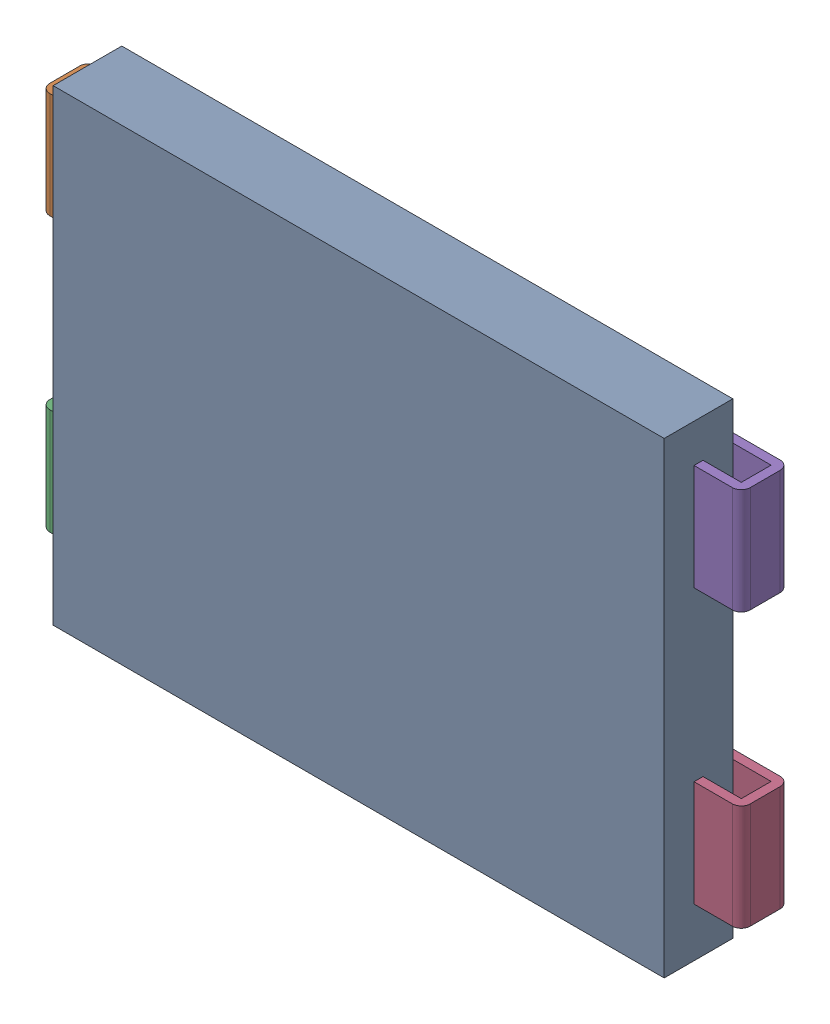
SolidWorks assembly Open CASCADE STEP translator 6.8 1.27.1, configuration Défaut. Lengths in mm.
Overall size (19.49 13 2.16).
5 component instances, 5 part files, 0 mates.
Components (placement in the parent):
- Body_1_13-1: Body_1_13 [Défaut] at origin size (17 13 1.91)
- Pin_1_10-1: Pin_1_10 [Défaut] at (-31.75 0 0) x (-1 0 0) z (0 0 1) size (3.61 2.95 1.33)
- Pin_2_10-1: Pin_2_10 [Défaut] at (-31.75 -15.24 0) x (-1 0 0) z (0 0 1) size (3.61 2.95 1.33)
- Pin_3_6-1: Pin_3_6 [Défaut] at origin size (3.61 2.95 1.33)
- Pin_4_4-1: Pin_4_4 [Défaut] at origin size (3.61 2.95 1.33)
